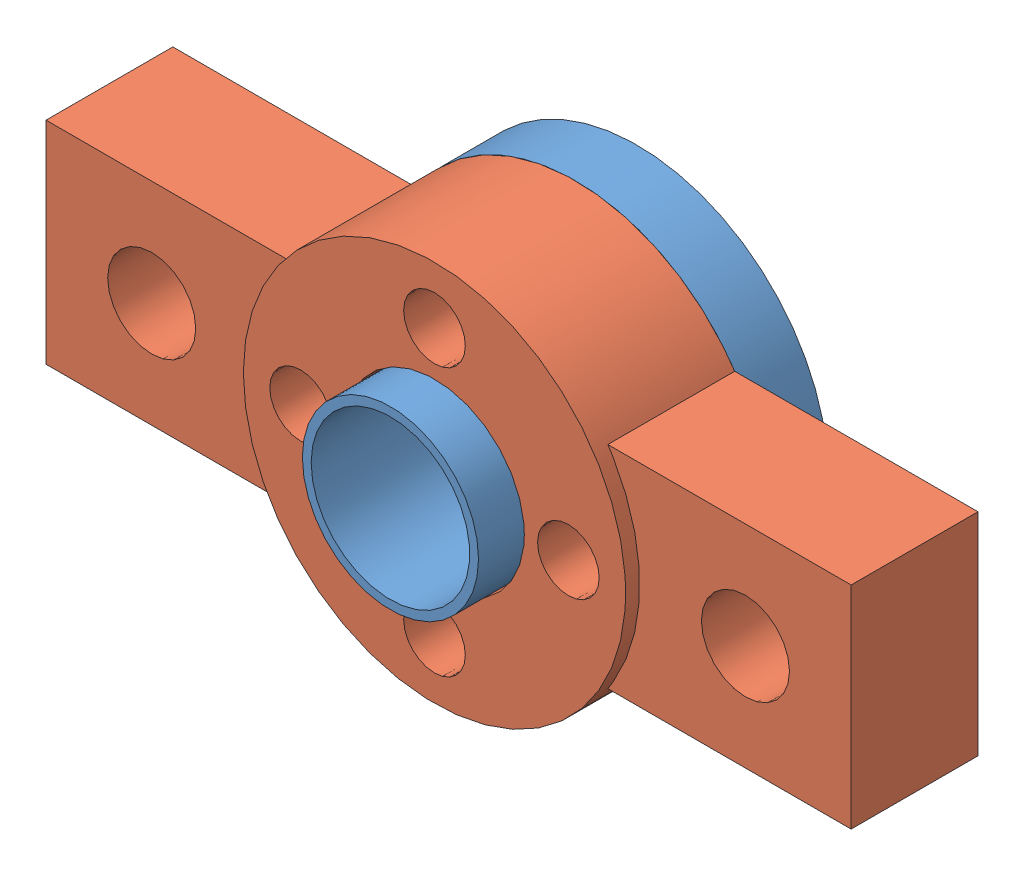
SolidWorks assembly Assem1, configuration Default. Lengths in mm.
Overall size (45.7 21.7 15).
4 component instances, 3 part files, 8 mates.
Components (placement in the parent):
- Dai-oc-Vit-me-1: Dai-oc-Vit-me [Default] at (5.8968 15.4807 14.9954) size (21.7 21.7 15)
- Dai-chua-vong-bi-1: Dai-chua-vong-bi [Default] at (5.8968 15.4807 19.4954) size (45.7 21.7 8)
- Vong-bi-3mm-1: Vong-bi-3mm [Default] at (22.7468 15.4807 19.6954) x (0.93225 -0.361815 0) z (-0.361815 -0.93225 0) size (7 3 7)
- Vong-bi-3mm-2: Vong-bi-3mm [Default] at (-10.9532 15.4807 19.6954) x (1 0 0) z (0 -1 0) size (7 3 7)
Mates (geometry in assembly coordinates):
- InPlace1: in place: plane of Dai-oc-Vit-me-1 through (5.8968 15.4807 19.4954) normal (0 0 1); plane of ? through (0 0 19.4954) normal (0 0 1); moOrthogonalPlaneRef_w of Dai-oc-Vit-me-1 through (5.8968 15.4807 19.4954) normal (0 0 1); plane of ? through (0 0 19.4954) normal (0 1 0); plane of Dai-oc-Vit-me-1 through (5.8968 15.4807 19.4954) normal (0 0 1); plane of ? through (0 0 19.4954) normal (1 0 0); plane of Dai-oc-Vit-me-1 through (5.8968 15.4807 19.4954) normal (0 0 1); unknown of Dai-chua-vong-bi-1
- Coincident1: coincident aligned: plane of ?; plane of ?
- Coincident2: coincident aligned: moOrthogonalPlaneRef_w of Dai-oc-Vit-me-1 through (5.8968 15.4807 19.4954) normal (0 1 0); plane of Part2^Assem1-1 through (5.8968 15.4807 19.4954) normal (0 1 0)
- Coincident3: coincident anti-aligned: moOrthogonalPlaneRef_w of Dai-oc-Vit-me-1 through (5.8968 15.4807 19.4954) normal (-1 0 0); plane of Part2^Assem1-1 through (5.8968 15.4807 19.4954) normal (1 0 0)
- Concentric1: concentric anti-aligned: cylinder of Dai-chua-vong-bi-1 through (22.7468 15.4807 22.6954) axis (0 0 -1) radius 3.55; cylinder of Vong-bi-3mm-1 through (22.7468 15.4807 19.6954) axis (0 0 1) radius 3.5
- Coincident4: coincident anti-aligned: plane of Dai-chua-vong-bi-1 through (5.8968 15.4807 22.6954) normal (0 0 -1); plane of Vong-bi-3mm-1 through (22.7468 15.4807 22.6954) normal (0 0 1)
- Concentric2: concentric anti-aligned: cylinder of Dai-chua-vong-bi-1 through (-10.9532 15.4807 22.6954) axis (0 0 -1) radius 3.55; cylinder of Vong-bi-3mm-2 through (-10.9532 15.4807 19.6954) axis (0 0 1) radius 3.5
- Coincident5: coincident aligned: plane of Vong-bi-3mm-1 through (22.7468 15.4807 19.6954) normal (0 0 -1); plane of Vong-bi-3mm-2 through (-10.9532 15.4807 19.6954) normal (0 0 -1)
